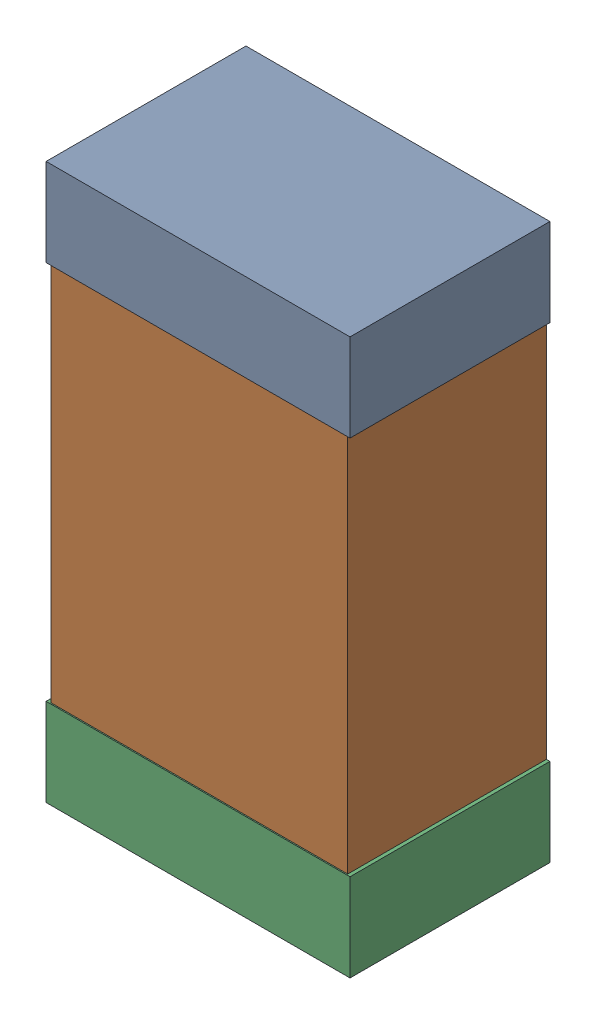
SolidWorks assembly R3_Motor_4Kanaloa_v2.0.0_Loko, configuration Default. Lengths in mm.
Overall size (1.3 2.38 0.85).
6 component instances, 2 part files, 0 mates.
Components (placement in the parent):
- 330415056_1-1: 330415056_1 [Default] at (55.6633 75.9554 0) size (1.3 0.38 0.85)
  - Extruded_29-1: Extruded_29 [Default] at origin size (1.3 0.38 0.85)
- 334787376_1-1: 334787376_1 [Default] at (55.6633 74.9554 0) size (1.27 2.2 0.85)
  - Extruded_30-1: Extruded_30 [Default] at origin size (1.27 2.2 0.85)
- 330415056_1-2: 330415056_1 [Default] at (55.6633 73.9554 0) size (1.3 0.38 0.85)
  - Extruded_29-1: Extruded_29 [Default] at origin size (1.3 0.38 0.85)
